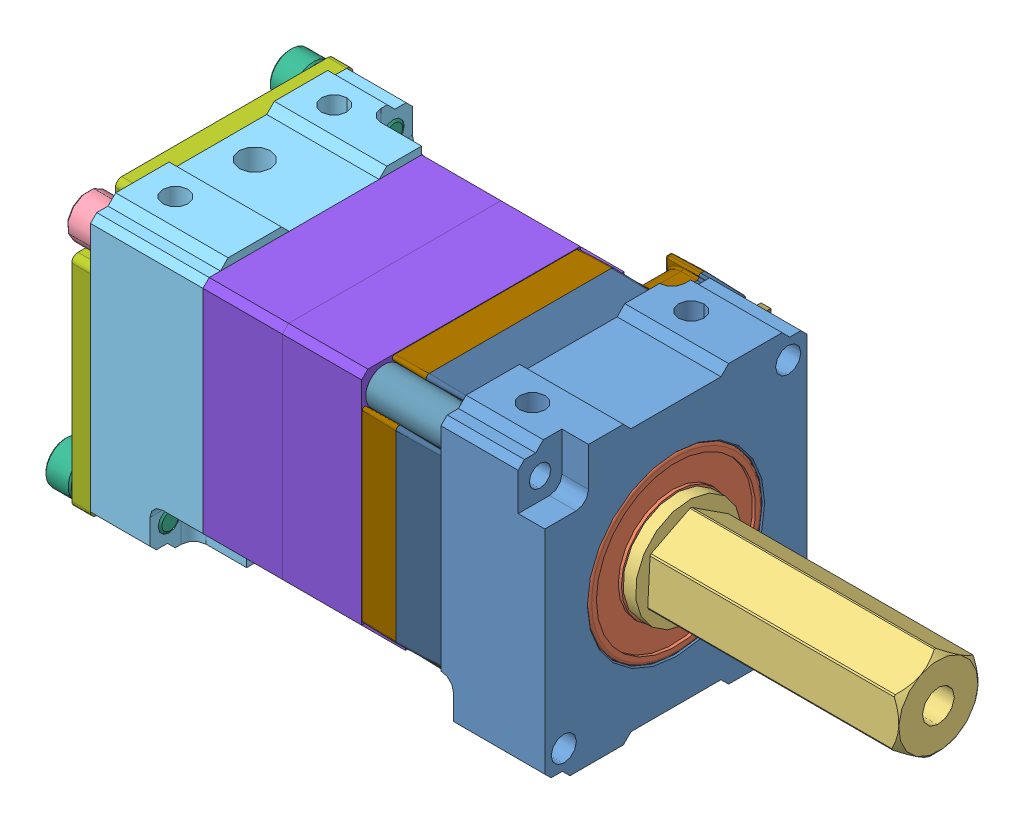
SolidWorks assembly VersaPlanetary_v2_Two_Stage_with_Encoder, configuration Default. Lengths in mm.
Overall size (121.79 44.49 58.8).
22 component instances, 16 part files, 29 mates.
Components (placement in the parent):
- 217-2625-026 Rev1-1: 217-2625-026 Rev1 [Default] at (25.4052 43.6717 -41.1353) x (0 -1 0) z (-1 0 0) size (44.45 42 18.13)
- 217-2742-001 Rev4-1: 217-2742-001 Rev4 [Default] at (30.4052 43.6717 -41.1353) x (1 0 0) z (0 -0.092627 0.995701) size (7 28 28)
- 217-2742-001 Rev4-2: 217-2742-001 Rev4 [Default] at (41.5302 43.6717 -41.1353) size (7 28 28)
- 217-2625-003 Rev1-1: 217-2625-003 Rev1 [Default] at (40.7778 43.6717 -41.1353) x (0 -0.891414 -0.45319) z (1 0 0) size (17 17 64.12)
- 832-2250-Base-Kit-Screw_SSA0832-0500ZC-1: 832-2250-Base-Kit-Screw_SSA0832-0500ZC [Default] at (-24.1948 26.1717 -58.6353) x (0 -0.767799 -0.640691) z (0 0.640691 -0.767799) size (6.73 61.21 6.73)
- 832-2250-Base-Kit-Screw_SSA0832-0500ZC-2: 832-2250-Base-Kit-Screw_SSA0832-0500ZC [Default] at (-24.1948 61.1717 -23.6353) x (0 0.961307 0.275478) z (0 -0.275478 0.961307) size (6.73 61.21 6.73)
- 217-2625-025 Rev1-1: 217-2625-025 Rev1 [Default] at (-16.6948 43.6717 -41.1353) x (0 -1 0) z (-1 0 0) size (44.45 42 18)
- 217-4649-002 Rev1_SSA0832-0500ZC-1: 217-4649-002 Rev1_SSA0832-0500ZC [Default] at (-27.1948 25.7111 -23.1748) x (0 0.33842 -0.940995) z (0 0.940995 0.33842) size (6.73 16.76 6.73)
- 217-4649-002 Rev1_SSA0832-0500ZC-2: 217-4649-002 Rev1_SSA0832-0500ZC [Default] at (-27.1948 61.6322 -59.0958) x (0 -0.308932 -0.951084) z (0 0.951084 -0.308932) size (6.73 16.76 6.73)
- 217-2822-003 Rev4-1: 217-2822-003 Rev4 [Default] at (-25.6948 43.6717 -41.1353) x (0 -1 0) z (-1 0 0) size (42 42 4.8)
- 217-2816-001 Rev1-1: 217-2816-001 Rev1 [Default] at (12.8552 43.6717 -41.1353) x (0 -1 0) z (1 0 0) size (42 42 14.5)
- 217-2816-001 Rev1-2: 217-2816-001 Rev1 [Default] at (0.1552 43.6717 -41.1353) x (0 -1 0) z (1 0 0) size (42 42 14.5)
- VersaPlanetary_Integrated_Encoder_217-5046-1: VersaPlanetary_Integrated_Encoder_217-5046 [Default] at (24.7052 43.6717 -41.1353) x (0 0 1) z (-1 0 0) size (58.06 43.13 18.16)
  - 217-4783-001 Rev3-1: 217-4783-001 Rev3 [Default] at (0 0 2.75) size (53.55 42 11.11)
  - 217-4783-002 Rev7_Sealed Config-1: 217-4783-002 Rev7_Sealed Config [Default] at (0 0 -7.2) x (0 1 0) z (0 0 1) size (42 51.56 9.32)
  - 217-4783-008 Rev2-1: 217-4783-008 Rev2 [Default] at (-20.05 0 2.2) x (0.307149 -0.951661 0) z (0.951661 0.307149 0) size (5 4 5)
  - PCBA Rev3-1: PCBA Rev3 [Default] at (-20.05 0 -2.1252) x (0 1 0) z (-1 0 0) size (15.93 10.15 24.44)
  - 217-2788-001 Rev3_57155K375-1: 217-2788-001 Rev3_57155K375 [Default] at (-20.05 0 3.8125) x (-0.99574 0.092202 0) z (0 0 1) size (9.53 9.53 3.17)
  - 217-4783-006 Rev3-1: 217-4783-006 Rev3 [Default] at (17.5 17.5 -0.85) x (-0.867641 0.497191 0) z (0 0 1) size (5.9 5.9 12.7)
  - 217-4783-006 Rev3-2: 217-4783-006 Rev3 [Default] at (-17.5 -17.5 -0.85) x (0.825154 -0.564908 0) z (0 0 1) size (5.9 5.9 12.7)
  - 217-4783-007 Rev1-1: 217-4783-007 Rev1 [Default] at (-16.45 0 -5.2) x (0 1 0) z (0 0 1) size (6 10.71 3.56)
  - 217-4783-003 Rev4-1: 217-4783-003 Rev4 [Default] at (-20.05 0 -1.02) x (0 1 0) z (0 0 1) size (23.4 21.71 4.21)
Mates (geometry in assembly coordinates):
- Concentric1: concentric aligned: cylinder of 217-2625-026 Rev1-1 through (48.5302 43.6717 -41.1353) axis (-1 0 0) radius 13.995; cylinder of 217-2742-001 Rev4-2 through (41.5302 43.6717 -41.1353) axis (-1 0 0) radius 14
- Coincident2: coincident aligned: plane of 217-2625-026 Rev1-1 through (48.5302 65.8967 -18.9103) normal (1 0 0); plane of 217-2742-001 Rev4-2 through (48.5302 56.4217 -41.1353) normal (1 0 0)
- Concentric2: concentric aligned: cylinder of 217-2625-026 Rev1-1 through (48.5302 43.6717 -41.1353) axis (-1 0 0) radius 13.995; cylinder of 217-2742-001 Rev4-1 through (30.4052 43.6717 -41.1353) axis (-1 0 0) radius 14
- Coincident3: coincident aligned: plane of 217-2625-026 Rev1-1 through (30.4052 43.6717 -41.1353) normal (-1 0 0); plane of 217-2742-001 Rev4-1 through (30.4052 57.6115 -39.8385) normal (-1 0 0)
- Concentric3: concentric aligned: cylinder of 217-2742-001 Rev4-2 through (41.5302 43.6717 -41.1353) axis (-1 0 0) radius 7.5; cylinder of 217-2625-003 Rev1-1 through (50.5302 43.6717 -41.1353) axis (-1 0 0) radius 7.4955
- Coincident4: coincident anti-aligned: plane of 217-2742-001 Rev4-2 through (48.5302 51.1717 -41.1353) normal (1 0 0); plane of 217-2625-003 Rev1-1 through (48.5302 43.6717 -41.1353) normal (-1 0 0)
- Concentric4: concentric aligned: circle of 217-2625-026 Rev1-1; circle of 217-2816-001 Rev1-1
- Parallel1: parallel aligned: plane of 217-2625-026 Rev1-1 through (30.4052 22.6717 -20.1353) normal (0 0 1); plane of 217-2816-001 Rev1-1 through (19.2052 64.6717 -20.1353) normal (0 0 1)
- Concentric5: concentric aligned: circle of 217-2816-001 Rev1-1; circle of 217-2816-001 Rev1-2
- Coincident6: coincident anti-aligned: plane of 217-2816-001 Rev1-1 through (6.5052 22.6717 -62.1353) normal (-1 0 0); plane of 217-2816-001 Rev1-2 through (6.5052 22.6717 -62.1353) normal (1 0 0)
- Parallel2: parallel aligned: plane of 217-2816-001 Rev1-1 through (19.2052 64.6717 -20.1353) normal (0 0 1); plane of 217-2816-001 Rev1-2 through (6.5052 64.6717 -20.1353) normal (0 0 1)
- Concentric6: concentric anti-aligned: circle of 217-2625-025 Rev1-1; circle of 217-2816-001 Rev1-2
- Coincident7: coincident anti-aligned: plane of 217-2625-025 Rev1-1 through (-6.1948 65.8967 -18.9103) normal (1 0 0); plane of 217-2816-001 Rev1-2 through (-6.1948 22.6717 -62.1353) normal (-1 0 0)
- Parallel3: parallel aligned: plane of 217-2625-025 Rev1-1 through (-6.1948 64.6717 -20.1353) normal (0 0 1); plane of 217-2816-001 Rev1-2 through (6.5052 64.6717 -20.1353) normal (0 0 1)
- Concentric7: concentric anti-aligned: circle of 217-2625-025 Rev1-1; circle of 217-2822-003 Rev4-1
- Coincident9: coincident anti-aligned: plane of 217-2625-025 Rev1-1 through (-24.1948 21.4467 -18.9103) normal (-1 0 0); plane of 217-2822-003 Rev4-1 through (-24.1948 43.6717 -41.1353) normal (1 0 0)
- Parallel4: parallel aligned: plane of 217-2625-025 Rev1-1 through (-6.1948 64.6717 -20.1353) normal (0 0 1); plane of 217-2822-003 Rev4-1 through (-27.1948 43.6717 -20.1353) normal (0 0 1)
- Concentric8: concentric anti-aligned: circle of 217-2625-026 Rev1-1; circle of VersaPlanetary_Integrated_Encoder_217-5046-1/217-4783-002 Rev7_Sealed Config-1
- Coincident10: coincident anti-aligned: plane of 217-2625-026 Rev1-1 through (31.9052 43.6717 -41.1353) normal (-1 0 0); plane of VersaPlanetary_Integrated_Encoder_217-5046-1/217-4783-006 Rev3-1 through (31.9052 58.6121 -25.102) normal (1 0 0)
- Concentric9: concentric anti-aligned: circle of 217-2625-026 Rev1-1; circle of VersaPlanetary_Integrated_Encoder_217-5046-1/217-4783-006 Rev3-1
- Coincident11: coincident anti-aligned: plane of 217-2816-001 Rev1-1 through (19.2052 22.6717 -62.1353) normal (1 0 0); plane of VersaPlanetary_Integrated_Encoder_217-5046-1/217-4783-006 Rev3-1 through (19.2052 58.6121 -25.102) normal (-1 0 0)
- Concentric10: concentric aligned: cylinder of 832-2250-Base-Kit-Screw_SSA0832-0500ZC-2 through (32.9552 61.1717 -23.6353) axis (-1 0 0) radius 2.0828; cylinder of 217-2625-025 Rev1-1 through (-24.1948 61.1717 -23.6353) axis (-1 0 0) radius 2.2479
- Coincident12: coincident anti-aligned: plane of 832-2250-Base-Kit-Screw_SSA0832-0500ZC-2 through (-24.1948 61.1717 -23.6353) normal (1 0 0); plane of 217-2625-025 Rev1-1 through (-24.1948 21.4467 -18.9103) normal (-1 0 0)
- Concentric11: concentric aligned: cylinder of 832-2250-Base-Kit-Screw_SSA0832-0500ZC-1 through (32.9552 26.1717 -58.6353) axis (-1 0 0) radius 2.0828; cylinder of 217-2625-025 Rev1-1 through (-24.1948 26.1717 -58.6353) axis (-1 0 0) radius 2.2479
- Coincident13: coincident anti-aligned: plane of 832-2250-Base-Kit-Screw_SSA0832-0500ZC-1 through (-24.1948 26.1717 -58.6353) normal (1 0 0); plane of 217-2625-025 Rev1-1 through (-24.1948 21.4467 -18.9103) normal (-1 0 0)
- Concentric12: concentric anti-aligned: cylinder of 217-2625-025 Rev1-1 through (6.5052 61.6322 -59.0958) axis (1 0 0) radius 1.7272; cylinder of 217-4649-002 Rev1_SSA0832-0500ZC-2 through (-14.4948 61.6322 -59.0958) axis (-1 0 0) radius 2.0828
- Coincident14: coincident anti-aligned: plane of 217-4649-002 Rev1_SSA0832-0500ZC-2 through (-27.1948 61.6322 -59.0958) normal (1 0 0); plane of 217-2822-003 Rev4-1 through (-27.1948 43.6717 -41.1353) normal (-1 0 0)
- Concentric13: concentric anti-aligned: cylinder of 217-2625-025 Rev1-1 through (6.5052 25.7111 -23.1748) axis (1 0 0) radius 1.7272; cylinder of 217-4649-002 Rev1_SSA0832-0500ZC-1 through (-14.4948 25.7111 -23.1748) axis (-1 0 0) radius 2.0828
- Coincident15: coincident anti-aligned: plane of 217-4649-002 Rev1_SSA0832-0500ZC-1 through (-27.1948 25.7111 -23.1748) normal (1 0 0); plane of 217-2822-003 Rev4-1 through (-27.1948 43.6717 -41.1353) normal (-1 0 0)
